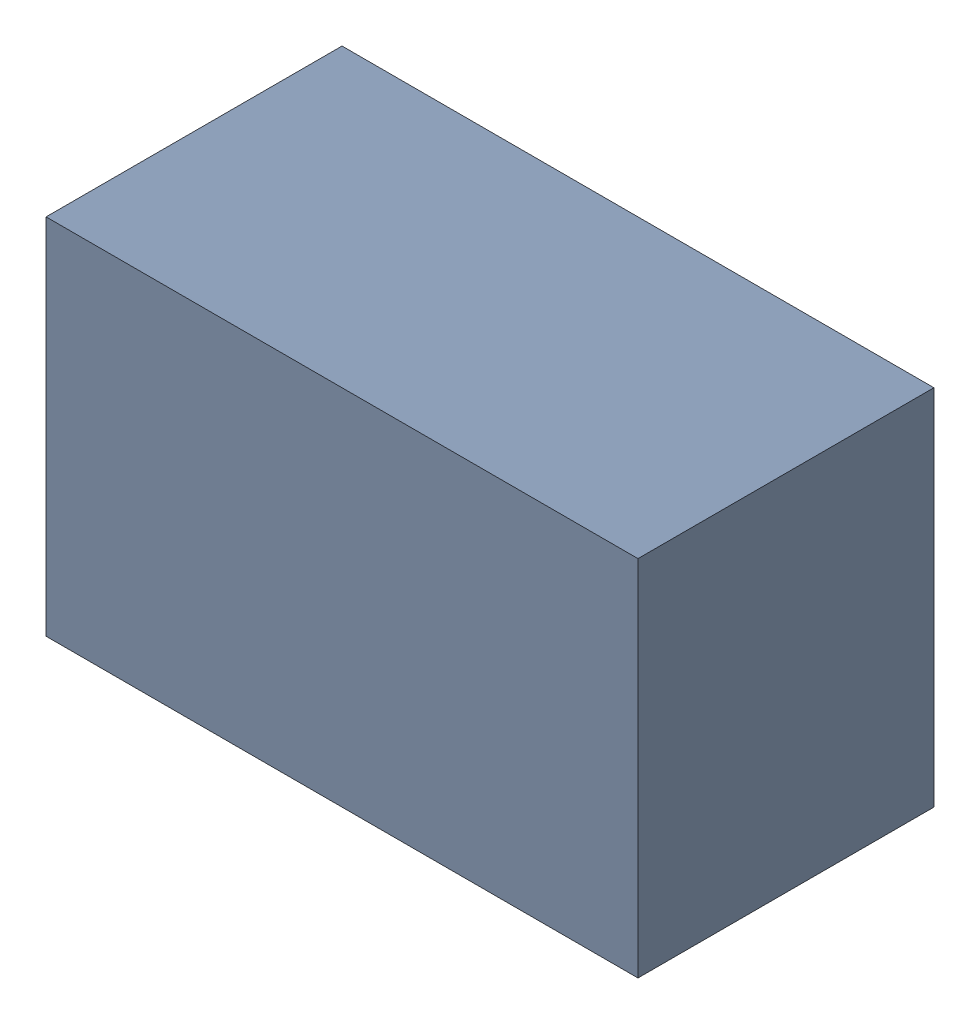
SolidWorks assembly Q10, configuration ﾃﾞﾌｫﾙﾄ. Lengths in mm.
Overall size (2.2 1.35 1.1).
2 component instances, 1 part files, 0 mates.
Components (placement in the parent):
- 689260288-1: 689260288 [ﾃﾞﾌｫﾙﾄ] at (15.25 59 0) size (2.2 1.35 1.1)
  - Extruded_22-1: Extruded_22 [ﾃﾞﾌｫﾙﾄ] at origin size (2.2 1.35 1.1)
